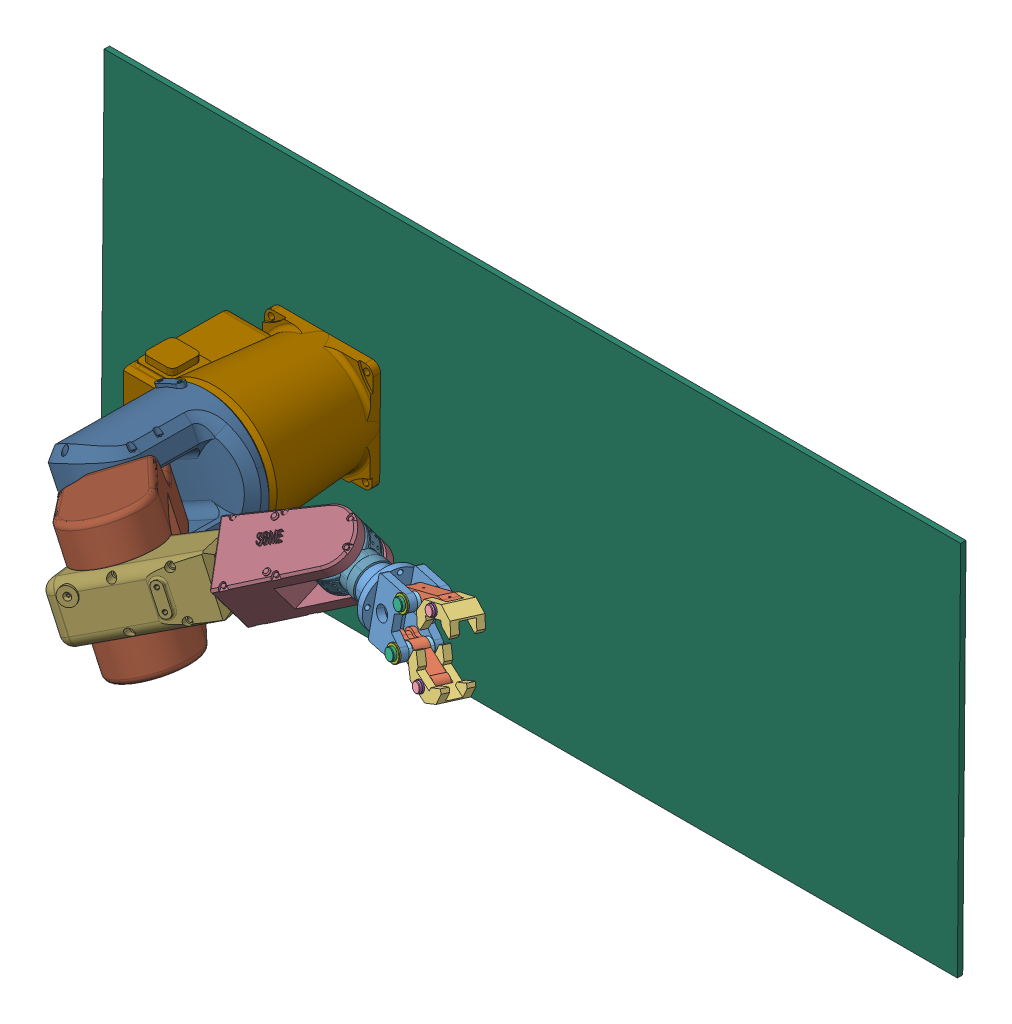
SolidWorks assembly 装配体1, configuration 默认. Lengths in mm.
Overall size (1600 700.06 739.49).
26 component instances, 15 part files, 0 mates.
Components (placement in the parent):
- 装配体1.STEP-1: 装配体1.STEP [默认] at origin size (1600 700.06 739.49)
  - joint7.STEP-1: joint7.STEP [默认] at (605.4527 442.7824 321.2816) x (-0.196317 0.166265 0.966341) z (-0.979649 0.008763 -0.200529) size (105 164.84 211.36)
    - 14.STEP-1: 14.STEP [默认] at origin size (105 105 121)
    - 18.STEP-1: 18.STEP [默认] at (0 38.5 -107) x (0 0.344424 -0.938814) z (1 0 0) size (109.57 29 28)
    - 19.STEP-1: 19.STEP [默认] at (0 69.5489 -159.698) x (0 0.330078 -0.943954) z (1 0 0) size (78 45 56)
    - 22.STEP-1: 22.STEP [默认] at (35 59.1654 -163.3289) x (0 -0.811761 -0.583989) z (-1 0 0) size (18 18 66)
    - 24.STEP-1: 24.STEP [默认] at (-21 38.5 -107) x (0 -0.533782 -0.845622) z (1 0 0) size (26 26 7)
    - 25.STEP-1: 25.STEP [默认] at (44 38.5 -107) x (-1 0 0) z (0 -0.659078 -0.752075) size (82 21 21)
    - 24.STEP-2: 24.STEP [默认] at (21 38.5 -107) x (0 -0.699829 -0.71431) z (-1 0 0) size (26 26 7)
    - 26.STEP-1: 26.STEP [默认] at (26.3555 38.5 -107) x (0 -0.33616 0.941805) z (0 0.941805 0.33616) size (30 3 30)
    - 23.STEP-1: 23.STEP [默认] at (28 59.1654 -163.3289) x (0 -0.043815 -0.99904) z (1 0 0) size (20 20 3)
    - 19.STEP-2: 19.STEP [默认] at (0 -69.5489 -159.698) x (0 -0.330078 -0.943954) z (-1 0 0) size (78 45 56)
    - 18.STEP-2: 18.STEP [默认] at (0 -38.5 -107) x (0 -0.344424 -0.938814) z (-1 0 0) size (109.57 29 28)
    - 22.STEP-2: 22.STEP [默认] at (35 -59.1654 -163.3289) x (0 -0.811761 0.583989) z (-1 0 0) size (18 18 66)
    - 23.STEP-2: 23.STEP [默认] at (31 -59.1654 -163.3289) x (0 0.043815 -0.99904) z (-1 0 0) size (20 20 3)
    - 25.STEP-2: 25.STEP [默认] at (44 -38.5 -107) x (-1 0 0) z (0 -0.659078 0.752075) size (82 21 21)
    - 26.STEP-2: 26.STEP [默认] at (26.3555 -38.5 -107) x (0 0.33616 0.941805) z (0 0.941805 -0.33616) size (30 3 30)
    - 24.STEP-3: 24.STEP [默认] at (14 -38.5 -107) x (0 0.699829 -0.71431) z (1 0 0) size (26 26 7)
    - 24.STEP-4: 24.STEP [默认] at (-14 -38.5 -107) x (0 0.533782 -0.845622) z (-1 0 0) size (26 26 7)
  - 0.STEP-1: 0.STEP [默认] at (0 189.2873 -190.9464) x (1 0 0) z (0 -0.999962 0.008727) size (286.68 237 244.97)
  - 1.STEP-1: 1.STEP [默认] at (0 191.2159 30.0452) x (-0.42745 0.904005 -0.007889) z (0.904039 0.427434 -0.00373) size (250 234.43 240.01)
  - 2.STEP-1: 2.STEP [默认] at (240.0095 308.0626 415.1132) x (-0.598725 -0.276542 0.7517) z (0.677358 0.326038 0.659458) size (160.79 235 500.03)
  - 3.STEP-1: 3.STEP [默认] at (389.0082 378.1065 368.2815) x (-0.835977 -0.391932 0.384099) z (-0.344135 -0.170778 -0.923258) size (250.17 103 166.59)
  - 4.STEP-1: 4.STEP [默认] at (527.1644 442.8785 304.804) x (0.835977 0.391932 -0.384099) z (-0.111573 0.806707 0.580324) size (240.41 124.26 113.23)
  - 5.STEP-1: 5.STEP [默认] at (527.0808 443.4835 305.2393) x (-0.166853 -0.590887 0.789311) z (-0.111573 0.806707 0.580324) size (100 133 68)
  - 零件1^装配体1.STEP-1: 零件1^装配体1.STEP [默认] at (0 189.2873 -190.9464) x (-1 0 0) z (0 -0.008727 -0.999962) size (1600 700 10)
